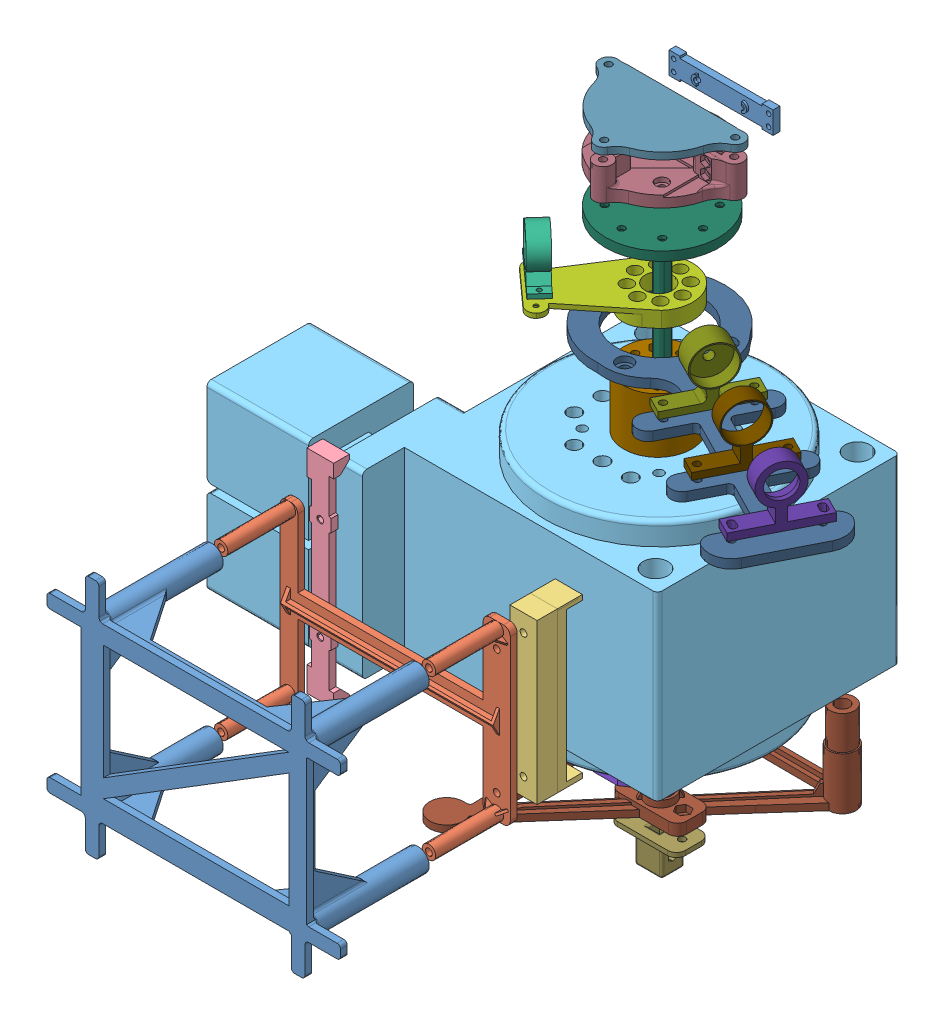
SolidWorks assembly 装配体3, configuration 默认. Lengths in mm.
Overall size (256.23 290.17 238.27).
19 component instances, 19 part files, 0 mates.
Components (placement in the parent):
- bottom_bottom-1: bottom_bottom [默认] at (-171.485 -91.8866 309.7623) x (0 -1 0) z (1 0 0) size (106.5 53 129.85)
- bottom_middle-1: bottom_middle [默认] at (-96.9882 -89.2508 219.6147) x (0 -1 0) z (-1 0 0) size (76.5 33 101.85)
- BottomPlate-1: BottomPlate [默认] at (-90.4762 -129.2837 200.6945) x (0 1 0) z (-1 0 0) size (70.61 20 12.13)
- bottomv2-1: bottomv2 [默认] at (-195.4462 -37.3986 208.2558) x (0 -1 0) z (1 0 0) size (94 7 11.85)
- 零件_转台模型-1: 零件_转台模型 [默认] at (-125.8107 -124.2593 125.1316) size (180.71 100 125.72)
- Diode_Fixer-1: Diode_Fixer [默认] at (-148.993 37.2514 150.053) x (-0.743145 0 -0.669131) z (0 1 0) size (25 8 20.5)
- Diode_FixerBase_V1_Part1-1: Diode_FixerBase_V1_Part1 [默认] at (-125.676 14.8132 125.3906) x (-0.743145 0 -0.669131) z (0.669131 0 -0.743145) size (30 7 58)
- DiodeBase_Part1-1: DiodeBase_Part1 [默认] at (-120.2715 -153.2321 134.1646) x (1 0 0) z (0 0 -1) size (41 49 44.38)
- DiodeBase_Part2-1: DiodeBase_Part2 [默认] at (-185.3721 -12.9146 116.904) size (30 46 30)
- Laser_Fixer_Base_V1_Part2_V2-1: Laser_Fixer_Base_V1_Part2_V2 [默认] at (-102.7192 2.3766 80.2993) x (-0.45399 0 0.891007) z (-0.891007 0 -0.45399) size (58 4 158)
- TriMirror_Base_V5-1: TriMirror_Base_V5 [默认] at (-106.6873 -177.4066 81.8198) x (-1 0 0) z (0 0 1) size (94.81 103.02 107.19)
- Trimirror_Base_V5_Fixer-1: Trimirror_Base_V5_Fixer [默认] at (-125.7495 -186.5576 124.9952) x (1 0 0) z (0 0 -1) size (30 15 15)
- Trimirror_Fixer_V2_Part1-1: Trimirror_Fixer_V2_Part1 [默认] at (-125.7789 69.286 123.9347) size (64 14 55)
- Trimirror_Fixer_V2_Part2-1: Trimirror_Fixer_V2_Part2 [默认] at (-67.7133 87.6081 88.2617) x (-1 0 0) z (0 0 1) size (64 4 38)
- TriMirrorBase_V5_Part2-1: TriMirrorBase_V5_Part2 [默认] at (-125.7484 46.7659 123.7647) size (50 130 50)
- Laser_Fixer_Fixer_Part1_1-1: Laser_Fixer_Fixer_Part1_1 [默认] at (-84.3522 27.784 146.3014) x (-0.45399 0 0.891007) z (0 1 0) size (36 10 26.75)
- Laser_Fixer_Fixer_Part1_2-1: Laser_Fixer_Fixer_Part1_2 [默认] at (-3.1425 27.5258 157.0133) x (-0.45399 0 0.891007) z (0 -1 0) size (36 8 26.75)
- Laser_Fixer_Fixer_Part1_3-1: Laser_Fixer_Fixer_Part1_3 [默认] at (-62.772 27.45 196.7066) x (-0.45399 0 0.891007) z (0 -1 0) size (36 8 26.75)
- TriMirrorHat_V1-1: TriMirrorHat_V1 [默认] at (-119.2198 84.2592 93.2969) x (1 0 0) z (0 -1 0) size (46 4 9.8)
